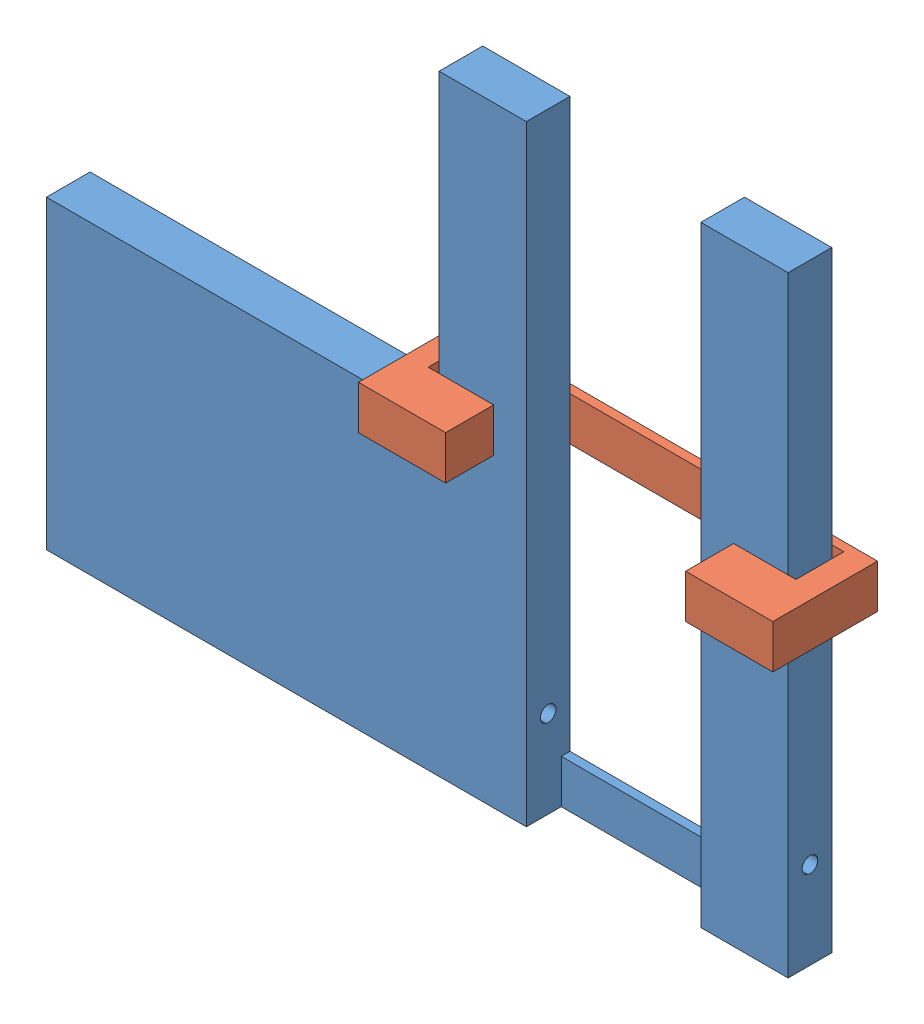
SolidWorks assembly assem2_2.2mm, configuration Default. Lengths in mm.
Overall size (35.5 28 4.8).
2 component instances, 2 part files, 3 mates.
Components (placement in the parent):
- fork2-1: fork2 [Default] at (-45.2021 -14.3239 23.6003) size (34 28 2)
- slider2-1: slider2 [Default] at (-46.7021 1.6761 23.0003) x (1 0 0) z (0 -1 0) size (19 4.8 2)
Mates (geometry in assembly coordinates):
- Coincident1: coincident anti-aligned: plane of fork2-1 through (-45.2021 -14.3239 25.6003) normal (0 0 1); plane of slider2-1 through (-31.7021 -0.3239 25.6003) normal (0 0 -1)
- Distance1: distance = 1.5 mm: line of slider2-1 through (-31.7021 -0.3239 25.6003) axis (0 1 0); line of fork2-1 through (-33.2021 13.6761 25.6003) axis (0 -1 0)
- LimitDistance1: limit distance = 0 mm anti-aligned: plane of slider2-1 through (-46.7021 -0.3239 23.0003) normal (0 -1 0); plane of fork2-1 through (-63.2021 -0.3239 23.6003) normal (0 1 0)
